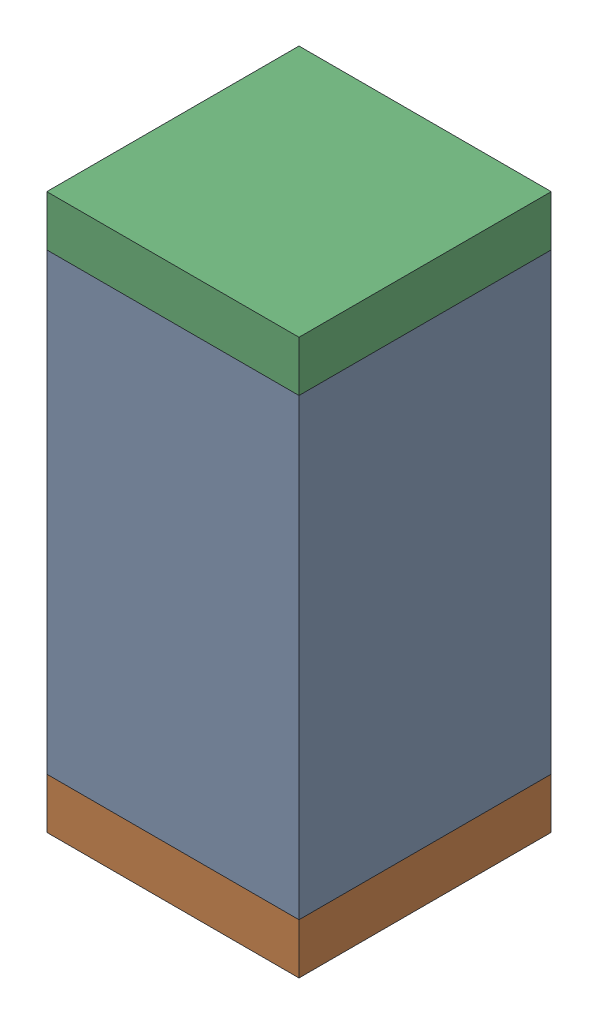
SolidWorks assembly C11, configuration Default. Lengths in mm.
Overall size (0.5 1.1 0.5).
6 component instances, 2 part files, 0 mates.
Components (placement in the parent):
- 791586336-1: 791586336 [Default] at (134.2 9.8 0) size (0.5 0.9 0.5)
  - Extruded_8-1: Extruded_8 [Default] at origin size (0.5 0.9 0.5)
- 810157360-1: 810157360 [Default] at (134.2 9.3 0) size (0.5 0.1 0.5)
  - Extruded_9-1: Extruded_9 [Default] at origin size (0.5 0.1 0.5)
- 810157360-2: 810157360 [Default] at (134.2 10.3 0) size (0.5 0.1 0.5)
  - Extruded_9-1: Extruded_9 [Default] at origin size (0.5 0.1 0.5)
